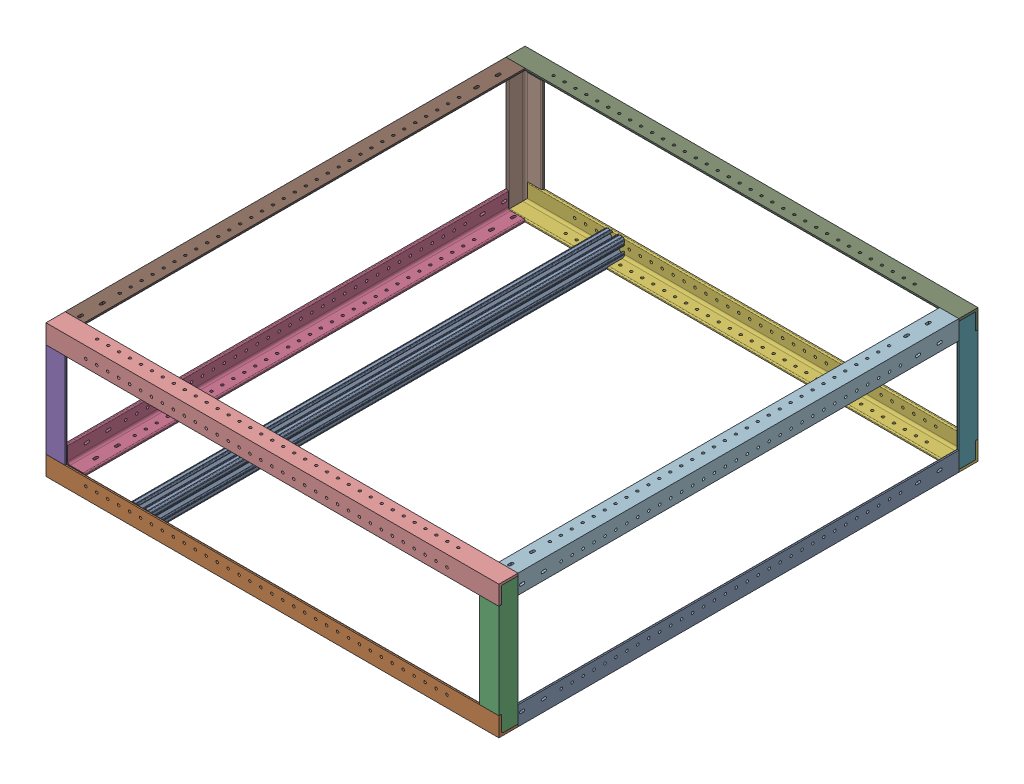
SolidWorks assembly Al_Frame_V2_Assembly, configuration Default. Lengths in mm.
Overall size (600 176.35 634.81).
13 component instances, 4 part files, 38 mates.
Components (placement in the parent):
- 1in_584mm_L-Extrusion-1: 1in_584mm_L-Extrusion [8982K404] at (129.4059 101.1157 -167.2524) size (25.4 25.4 584)
- 1in_600mm_L-Extrusion-1: 1in_600mm_L-Extrusion [8982K404] at (151.7059 101.1157 455.0476) x (0 0 1) z (-1 0 0) size (25.4 25.4 600)
- 1in_170mm_L-Extrusion-1: 1in_170mm_L-Extrusion [8982K404] at (129.4059 -348.0093 455.0526) x (1 0 0) z (0 1 0) size (25.4 25.4 170)
- 1in_584mm_L-Extrusion-3: 1in_584mm_L-Extrusion [8982K404] at (-445.1941 101.1157 467.9476) x (-1 0 0) z (0 0 -1) size (25.4 25.4 584)
- 1in_170mm_L-Extrusion-5: 1in_170mm_L-Extrusion [8982K404] at (-445.1941 701.1907 455.0476) x (-1 0 0) z (0 -1 0) size (25.4 25.4 170)
- 1in_600mm_L-Extrusion-3: 1in_600mm_L-Extrusion [8982K404] at (-467.4941 101.1157 -154.3524) x (0 0 -1) z (1 0 0) size (25.4 25.4 600)
- 1in_170mm_L-Extrusion-9: 1in_170mm_L-Extrusion [8982K404] at (129.4059 701.1907 -154.3524) x (1 0 0) z (0 -1 0) size (25.4 25.4 170)
- 1in_170mm_L-Extrusion-8: 1in_170mm_L-Extrusion [8982K404] at (-445.1941 -348.0093 -154.3524) x (-1 0 0) z (0 1 0) size (25.4 25.4 170)
- 1in_600mm_L-Extrusion-4: 1in_600mm_L-Extrusion [8982K404] at (151.7059 252.0657 -154.3524) x (0 0 -1) z (-1 0 0) size (25.4 25.4 600)
- 1in_600mm_L-Extrusion-5: 1in_600mm_L-Extrusion [8982K404] at (151.7059 252.0657 455.0476) x (0 1 0) z (-1 0 0) size (25.4 25.4 600)
- 1in_584mm_L-Extrusion-4: 1in_584mm_L-Extrusion [8982K404] at (-445.1941 252.0657 -167.2524) x (-1 0 0) z (0 0 1) size (25.4 25.4 584)
- 1in_584mm_L-Extrusion-5: 1in_584mm_L-Extrusion [8982K404] at (129.4059 252.0657 -167.2524) x (0 1 0) z (0 0 1) size (25.4 25.4 584)
- 628mm_T-Slot-1: 628mm_T-Slot [47065T412] at (-335.7453 101.1157 293.3226) size (25.4 25.4 628.45)
Mates (geometry in assembly coordinates):
- Coincident1: coincident anti-aligned: plane of 1in_584mm_L-Extrusion-1 through (140.5184 112.2282 442.3476) normal (0 0 1); plane of 1in_600mm_L-Extrusion-1 through (-457.8941 90.0032 442.3476) normal (0 0 -1)
- Coincident2: coincident aligned: plane of 1in_584mm_L-Extrusion-1 through (135.7559 91.5907 442.3476) normal (0 1 0); plane of 1in_600mm_L-Extrusion-1 through (-457.8941 91.5907 461.3976) normal (0 1 0)
- Coincident3: coincident aligned: plane of 1in_584mm_L-Extrusion-1 through (142.1059 88.4157 442.3476) normal (1 0 0); plane of 1in_600mm_L-Extrusion-1 through (142.1059 113.8157 437.2676) normal (1 0 0)
- Coincident7: coincident aligned: plane of 1in_584mm_L-Extrusion-1 through (142.1059 88.4157 442.3476) normal (1 0 0); plane of 1in_170mm_L-Extrusion-1 through (142.1059 261.5907 467.7526) normal (1 0 0)
- Coincident8: coincident anti-aligned: plane of 1in_600mm_L-Extrusion-1 through (-457.8941 91.5907 461.3976) normal (0 1 0); plane of 1in_170mm_L-Extrusion-1 through (111.6259 91.5907 442.3526) normal (0 -1 0)
- Coincident14: coincident aligned: plane of 1in_600mm_L-Extrusion-1 through (-457.8941 112.2282 464.5726) normal (0 0 -1); plane of 160modified-2 through (-443.4816 251.5907 464.5726) normal (0 0 -1)
- Coincident17: coincident aligned: plane of 1in_584mm_L-Extrusion-1 through (111.6259 113.8157 -141.6524) normal (0 0 -1); plane of 1 inch 584mm L Angle-2 through (116.7059 72.5505 -121.6524) normal (0 0 -1)
- Coincident19: coincident aligned: plane of 1in_600mm_L-Extrusion-1 through (-457.8941 112.2282 466.1601) normal (-1 0 0); plane of 1in_584mm_L-Extrusion-3 through (-457.8941 88.4157 -141.6524) normal (-1 0 0)
- Coincident20: coincident aligned: plane of 1in_600mm_L-Extrusion-1 through (-457.8941 88.4157 442.3476) normal (0 -1 0); plane of 1in_584mm_L-Extrusion-3 through (-432.4941 88.4157 -141.6524) normal (0 -1 0)
- Coincident21: coincident anti-aligned: plane of 1in_600mm_L-Extrusion-1 through (-457.8941 90.0032 442.3476) normal (0 0 -1); plane of 1in_584mm_L-Extrusion-3 through (-427.4141 113.8157 442.3476) normal (0 0 1)
- Coincident22: coincident aligned: plane of 1in_584mm_L-Extrusion-3 through (-454.7191 112.2282 -141.6524) normal (1 0 0); plane of 1in_170mm_L-Extrusion-5 through (-454.7191 91.5907 443.9351) normal (1 0 0)
- Coincident23: coincident aligned: plane of 1in_600mm_L-Extrusion-1 through (-457.8941 88.4157 467.7476) normal (0 0 1); plane of 1in_170mm_L-Extrusion-5 through (-432.4941 91.5907 467.7476) normal (0 0 1)
- Coincident24: coincident aligned: plane of 1in_584mm_L-Extrusion-3 through (-457.8941 88.4157 -141.6524) normal (-1 0 0); plane of 1in_170mm_L-Extrusion-5 through (-457.8941 91.5907 467.7476) normal (-1 0 0)
- Coincident26: coincident anti-aligned: plane of 1in_584mm_L-Extrusion-1 through (111.6259 113.8157 -141.6524) normal (0 0 -1); plane of 1in_600mm_L-Extrusion-3 through (142.1059 90.0032 -141.6524) normal (0 0 1)
- Coincident27: coincident aligned: plane of 1in_584mm_L-Extrusion-1 through (135.7559 91.5907 442.3476) normal (0 1 0); plane of 1in_600mm_L-Extrusion-3 through (142.1059 91.5907 -160.7024) normal (0 1 0)
- Coincident28: coincident aligned: plane of 1in_584mm_L-Extrusion-1 through (142.1059 88.4157 442.3476) normal (1 0 0); plane of 1in_600mm_L-Extrusion-3 through (142.1059 112.2282 -165.4649) normal (1 0 0)
- Coincident30: coincident: plane of 1in_600mm_L-Extrusion-3 through (142.1059 112.2282 -163.8774) normal (0 0 1); plane of 160modified-6 through (118.2934 253.0392 -143.8774) normal (0 0 1)
- Coincident31: coincident aligned: plane of 1in_584mm_L-Extrusion-1 through (138.9309 112.2282 442.3476) normal (-1 0 0); plane of 160modified-6 through (138.9309 253.0392 -140.7024) normal (-1 0 0)
- Coincident32: coincident aligned: plane of 1in_584mm_L-Extrusion-1 through (142.1059 88.4157 442.3476) normal (1 0 0); plane of 1in_170mm_L-Extrusion-9 through (142.1059 91.5907 -167.0524) normal (1 0 0)
- Coincident33: coincident aligned: plane of 1in_600mm_L-Extrusion-3 through (142.1059 88.4157 -167.0524) normal (0 0 -1); plane of 1in_170mm_L-Extrusion-9 through (116.7059 91.5907 -167.0524) normal (0 0 -1)
- Coincident35: coincident aligned: plane of 1in_584mm_L-Extrusion-3 through (-457.8941 88.4157 -141.6524) normal (-1 0 0); plane of 1in_170mm_L-Extrusion-8 through (-457.8941 261.5907 -167.0524) normal (-1 0 0)
- Coincident36: coincident aligned: plane of 1in_600mm_L-Extrusion-3 through (142.1059 88.4157 -167.0524) normal (0 0 -1); plane of 1in_170mm_L-Extrusion-8 through (-432.4941 261.5907 -167.0524) normal (0 0 -1)
- Coincident42: coincident aligned: plane of 1in_170mm_L-Extrusion-5 through (-432.4941 91.5907 467.7476) normal (0 0 1); plane of 1in_600mm_L-Extrusion-5 through (-457.8941 239.3657 467.7476) normal (0 0 1)
- Coincident43: coincident anti-aligned: plane of 1in_170mm_L-Extrusion-5 through (-427.4141 261.5907 442.3476) normal (0 1 0); plane of 1in_600mm_L-Extrusion-5 through (-457.8941 261.5907 443.9351) normal (0 -1 0)
- Coincident44: coincident aligned: plane of 1in_170mm_L-Extrusion-5 through (-457.8941 91.5907 467.7476) normal (-1 0 0); plane of 1in_600mm_L-Extrusion-5 through (-457.8941 263.1782 443.9351) normal (-1 0 0)
- Coincident46: coincident aligned: plane of 1in_170mm_L-Extrusion-8 through (-457.8941 261.5907 -167.0524) normal (-1 0 0); plane of 1in_584mm_L-Extrusion-4 through (-457.8941 264.7657 442.3476) normal (-1 0 0)
- Coincident47: coincident anti-aligned: plane of 1in_170mm_L-Extrusion-5 through (-456.3066 91.5907 442.3476) normal (0 0 -1); plane of 1in_584mm_L-Extrusion-4 through (-456.3066 240.9532 442.3476) normal (0 0 1)
- Coincident48: coincident aligned: plane of 1in_170mm_L-Extrusion-1 through (142.1059 261.5907 467.7526) normal (1 0 0); plane of 1in_584mm_L-Extrusion-5 through (142.1059 239.3657 442.3476) normal (1 0 0)
- Coincident49: coincident aligned: plane of 1in_600mm_L-Extrusion-5 through (-457.8941 264.7657 467.7476) normal (0 1 0); plane of 1in_584mm_L-Extrusion-5 through (142.1059 264.7657 442.3476) normal (0 1 0)
- Coincident51: coincident aligned: plane of 1in_170mm_L-Extrusion-9 through (116.7059 91.5907 -167.0524) normal (0 0 -1); plane of 1in_600mm_L-Extrusion-4 through (-457.8941 264.7657 -167.0524) normal (0 0 -1)
- Coincident53: coincident anti-aligned: plane of 1in_600mm_L-Extrusion-3 through (142.1059 91.5907 -160.7024) normal (0 1 0); plane of 1in_170mm_L-Extrusion-8 through (-427.4141 91.5907 -141.6524) normal (0 -1 0)
- Coincident54: coincident aligned: plane of 1in_170mm_L-Extrusion-8 through (-432.4941 261.5907 -167.0524) normal (0 0 -1); plane of 1in_600mm_L-Extrusion-4 through (-457.8941 264.7657 -167.0524) normal (0 0 -1)
- Coincident55: coincident aligned: plane of 1in_170mm_L-Extrusion-8 through (-457.8941 261.5907 -167.0524) normal (-1 0 0); plane of 1in_600mm_L-Extrusion-4 through (-457.8941 240.9532 -165.4649) normal (-1 0 0)
- Coincident56: coincident anti-aligned: plane of 1in_170mm_L-Extrusion-8 through (-456.3066 261.5907 -143.2399) normal (0 1 0); plane of 1in_600mm_L-Extrusion-4 through (-457.8941 261.5907 -160.7024) normal (0 -1 0)
- Coincident57: coincident aligned: plane of 1in_600mm_L-Extrusion-4 through (-457.8941 264.7657 -141.6524) normal (0 1 0); plane of 1in_584mm_L-Extrusion-4 through (-432.4941 264.7657 442.3476) normal (0 1 0)
- Coincident58: coincident anti-aligned: plane of 1in_600mm_L-Extrusion-3 through (142.1059 112.2282 -163.8774) normal (0 0 1); plane of 628mm_T-Slot-1 through (-291.5549 89.3549 -163.8774) normal (0 0 -1)
- Coincident59: coincident aligned: plane of 1in_600mm_L-Extrusion-1 through (-457.8941 88.4157 442.3476) normal (0 -1 0); plane of 628mm_T-Slot-1 through (-291.5549 88.4157 750.5226) normal (0 -1 0)
- Distance1: distance = 100 mm anti-aligned: plane of 628mm_T-Slot-1 through (-332.4941 89.6864 750.5226) normal (-1 0 0); plane of 1in_584mm_L-Extrusion-3 through (-432.4941 90.0032 -141.6524) normal (1 0 0)
